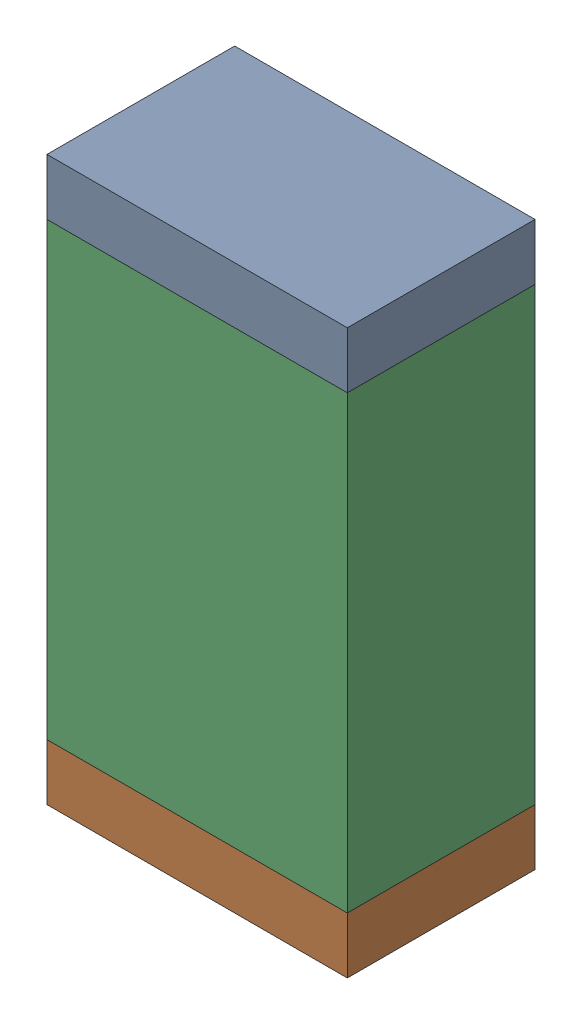
SolidWorks assembly R47, configuration Default. Lengths in mm.
Overall size (0.8 1.5 0.5).
6 component instances, 2 part files, 0 mates.
Components (placement in the parent):
- 810156592-1: 810156592 [Default] at (106.6 59.975 0) size (0.8 0.15 0.5)
  - Extruded_7-1: Extruded_7 [Default] at origin size (0.8 0.15 0.5)
- 810156592-2: 810156592 [Default] at (106.6 58.625 0) size (0.8 0.15 0.5)
  - Extruded_7-1: Extruded_7 [Default] at origin size (0.8 0.15 0.5)
- 810156976-1: 810156976 [Default] at (106.6 59.3 0) size (0.8 1.2 0.5)
  - Extruded_6-1: Extruded_6 [Default] at origin size (0.8 1.2 0.5)
